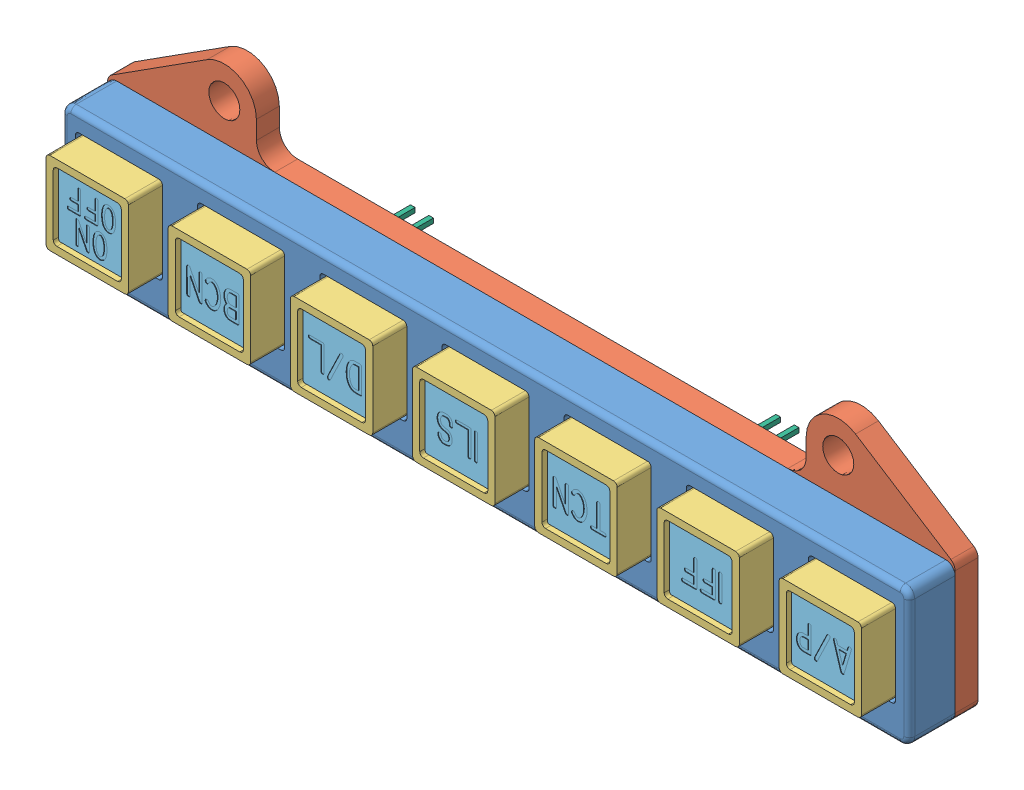
SolidWorks assembly AP Switch Module, configuration Default. Lengths in mm.
Overall size (117.47 28.58 21.11).
24 component instances, 6 part files, 17 mates.
Components (placement in the parent):
- AP Module FWD Body-1: AP Module FWD Body [Default] at origin size (117.47 19.05 6.35)
- AP Module Mounting Plate-1: AP Module Mounting Plate [Default] at (0 0 3.175) x (-1 0 0) z (0 0 -1) size (117.47 28.58 3.17)
- UFC Square Button-1: UFC Square Button [Default] at (50.8 -56.6199 9.5377) size (12.95 12.95 7.56)
- AP Square Button Spacer-1: AP Square Button Spacer [AP] at (50.8 -56.6199 10.2442) size (8.92 8.92 1.59)
- UFC Square Button Legend-1: UFC Square Button Legend [AP] at (50.8 -56.6199 11.8317) size (8.92 8.92 1.59)
- ufc_v4_ap-1: ufc_v4_ap [Default] at (0.02 -56.6243 1.397) size (115 14.5 17.44)
- UFC Square Button Legend-9: UFC Square Button Legend [IFF] at (33.8667 -56.6199 11.8317) size (8.92 8.92 1.59)
- UFC Square Button Legend-10: UFC Square Button Legend [TCN] at (16.9333 -56.6199 11.8317) size (8.92 8.92 1.59)
- UFC Square Button Legend-11: UFC Square Button Legend [ILS] at (0 -56.6199 11.8317) size (8.92 8.92 1.59)
- UFC Square Button Legend-12: UFC Square Button Legend [DL] at (-16.9333 -56.6199 11.8317) size (8.92 8.92 1.59)
- UFC Square Button Legend-13: UFC Square Button Legend [BCN] at (-33.8667 -56.6199 11.8317) size (8.92 8.92 1.59)
- UFC Square Button Legend-14: UFC Square Button Legend [ON-OFF] at (-50.8 -56.6199 11.8317) size (8.92 8.92 1.59)
- AP Square Button Spacer-2: AP Square Button Spacer [AP] at (33.8667 -56.6199 10.2442) size (8.92 8.92 1.59)
- AP Square Button Spacer-3: AP Square Button Spacer [AP] at (16.9333 -56.6199 10.2442) size (8.92 8.92 1.59)
- AP Square Button Spacer-4: AP Square Button Spacer [AP] at (0 -56.6199 10.2442) size (8.92 8.92 1.59)
- AP Square Button Spacer-5: AP Square Button Spacer [AP] at (-16.9333 -56.6199 10.2442) size (8.92 8.92 1.59)
- AP Square Button Spacer-6: AP Square Button Spacer [AP] at (-33.8667 -56.6199 10.2442) size (8.92 8.92 1.59)
- AP Square Button Spacer-7: AP Square Button Spacer [AP] at (-50.8 -56.6199 10.2442) size (8.92 8.92 1.59)
- UFC Square Button-8: UFC Square Button [Default] at (33.8667 -56.6199 9.5377) size (12.95 12.95 7.56)
- UFC Square Button-9: UFC Square Button [Default] at (16.9333 -56.6199 9.5377) size (12.95 12.95 7.56)
- UFC Square Button-10: UFC Square Button [Default] at (0 -56.6199 9.5377) size (12.95 12.95 7.56)
- UFC Square Button-11: UFC Square Button [Default] at (-16.9333 -56.6199 9.5377) size (12.95 12.95 7.56)
- UFC Square Button-12: UFC Square Button [Default] at (-33.8667 -56.6199 9.5377) size (12.95 12.95 7.56)
- UFC Square Button-13: UFC Square Button [Default] at (-50.8 -56.6199 9.5377) size (12.95 12.95 7.56)
Mates (geometry in assembly coordinates):
- Symmetric1: symmetric aligned: plane of AP Module FWD Body-1 through (44.7675 -50.5874 0) normal (1 0 0); plane of AP Module FWD Body-1 through (56.8325 -62.6524 0) normal (-1 0 0); plane of UFC Square Button-1 through (50.8 -56.6199 9.5377) normal (1 0 0)
- Symmetric2: symmetric aligned: plane of AP Module FWD Body-1 through (44.7675 -62.6524 0) normal (0 1 0); plane of AP Module FWD Body-1 through (56.8325 -50.5874 0) normal (0 -1 0); plane of UFC Square Button-1 through (50.8 -56.6199 9.5377) normal (0 1 0)
- Coincident15: coincident: plane of AP Module FWD Body-1 through (0 -57.6105 7.9502) normal (0 0 -1); plane of UFC Square Button-1 through (50.8 -56.6199 7.9502) normal (0 0 1)
- Concentric1: concentric aligned: cylinder of 99461A505 - PHS, 0-42 X .125, SELF TAPPING, 18-8-1 through (50.8 -56.6199 5.3721) axis (0 0 1) radius 1.4732; cylinder of UFC Square Button-1 through (50.8 -56.6199 12.5222) axis (0 0 1) radius 0.5906
- Coincident11: coincident anti-aligned: plane of 99461A505 - PHS, 0-42 X .125, SELF TAPPING, 18-8-1 through (50.8 -56.6199 6.3627) normal (0 0 1); plane of UFC Square Button-1 through (50.8 -56.6199 6.3627) normal (0 0 -1)
- Coincident12: coincident aligned: plane of UFC Square Button-1 through (50.8 -56.6199 9.5377) normal (1 0 0); plane of UFC Square Button Legend-1 through (50.8 -56.6199 11.8317) normal (1 0 0)
- Coincident13: coincident aligned: plane of UFC Square Button-1 through (50.8 -56.6199 9.5377) normal (0 1 0); plane of UFC Square Button Legend-1 through (50.8 -56.6199 11.8317) normal (0 1 0)
- Coincident19: coincident aligned: plane of AP Module FWD Body-1 through (-58.7375 -67.1355 128.5346) normal (0 -1 0); plane of AP Module Mounting Plate-1 through (58.7375 -67.1355 0) normal (0 -1 0)
- Coincident20: coincident aligned: plane of AP Module FWD Body-1 through (-58.7375 -48.0855 128.5346) normal (-1 0 0); plane of AP Module Mounting Plate-1 through (-58.7375 -67.1355 0) normal (-1 0 0)
- Coincident21: coincident: plane of AP Module FWD Body-1 through (48.4188 -43.323 3.175) normal (0 0 -1); plane of AP Module Mounting Plate-1 through (-42.545 -43.0055 3.175) normal (0 0 1)
- Coincident23: coincident anti-aligned: plane of AP Module Mounting Plate-1 through (55.52 -61.8743 1.397) normal (0 0 1); plane of ufc_v4_ap-1 through (0.02 -56.6243 1.397) normal (0 0 -1)
- Width2: width anti-aligned: plane of AP Module FWD Body-1 through (-6.0325 -62.6524 0) normal (0 1 0); plane of AP Module FWD Body-1 through (6.0325 -50.5874 0) normal (0 -1 0); plane of ufc_v4_ap-1 through (-3.1075 -59.6199 8.087) normal (0 -1 0); plane of ufc_v4_ap-1 through (-3.1325 -53.6199 2.807) normal (0 1 0)
- Width3: width anti-aligned: plane of AP Module FWD Body-1 through (-6.0325 -50.5874 0) normal (1 0 0); plane of AP Module FWD Body-1 through (6.0325 -62.6524 0) normal (-1 0 0); plane of ufc_v4_ap-1 through (-3 -59.9199 2.807) normal (-1 0 0); plane of ufc_v4_ap-1 through (3 -59.9199 8.087) normal (1 0 0)
- Width4: width anti-aligned: plane of AP Square Button Spacer-1 through (55.261 -60.8269 11.8317) normal (1 0 0); plane of AP Square Button Spacer-1 through (46.339 -52.4129 11.8317) normal (-1 0 0); plane of UFC Square Button-1 through (55.515 -51.9049 10.2442) normal (-1 0 0); plane of UFC Square Button-1 through (46.085 -51.9049 10.2442) normal (1 0 0)
- Width6: width anti-aligned: plane of AP Square Button Spacer-1 through (55.007 -52.1589 11.8317) normal (0 1 0); plane of AP Square Button Spacer-1 through (46.593 -61.0809 11.8317) normal (0 -1 0); plane of UFC Square Button-1 through (46.085 -51.9049 10.2442) normal (0 -1 0); plane of UFC Square Button-1 through (46.085 -61.3349 10.2442) normal (0 1 0)
- Coincident24: coincident anti-aligned: plane of UFC Square Button-1 through (50.8 -56.6199 10.2442) normal (0 0 1); plane of AP Square Button Spacer-1 through (55.007 -52.4129 10.2442) normal (0 0 -1)
- Coincident25: coincident anti-aligned: plane of AP Square Button Spacer-1 through (55.007 -52.4129 11.8317) normal (0 0 1); plane of UFC Square Button Legend-1 through (55.007 -52.4129 11.8317) normal (0 0 -1)
